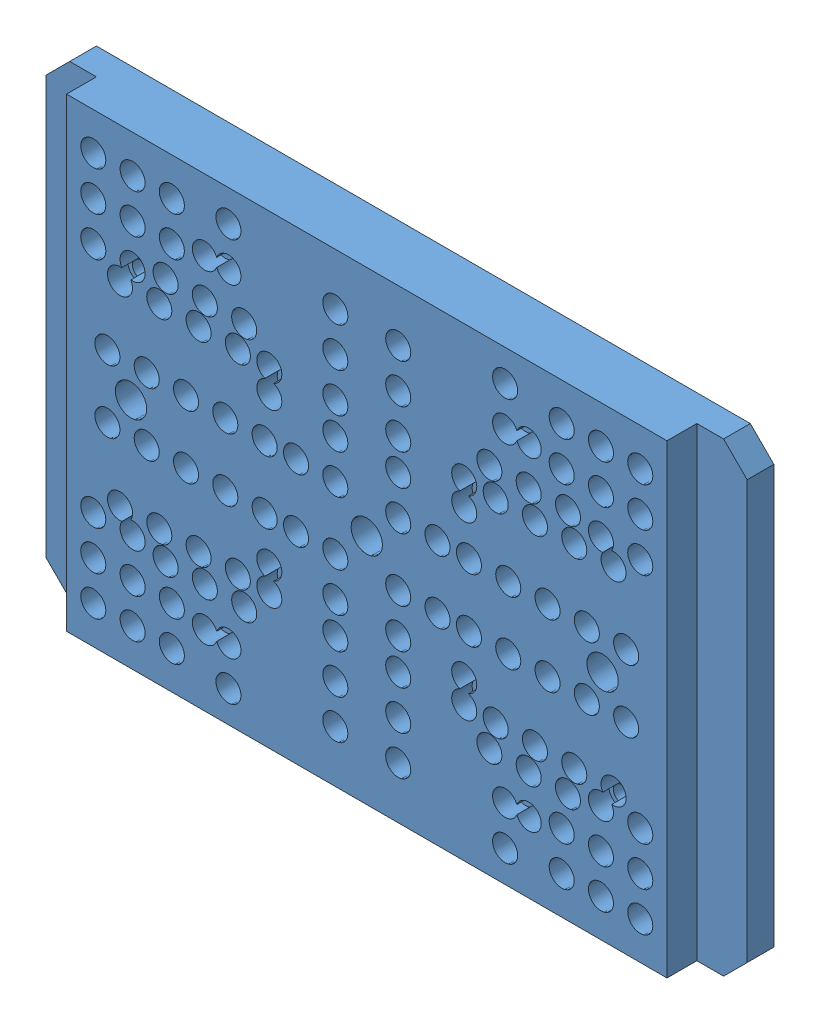
SolidWorks assembly H1000 C800 ROBO 5X v1, configuration Défaut. Lengths in mm.
Overall size (446 296 36).
2 component instances, 1 part files, 0 mates.
Components (placement in the parent):
- H1000 C800 ROBO 5X v1(2)^H1000 C800 ROBO 5X-1: H1000 C800 ROBO 5X v1(2)^H1000 C800 ROBO 5X [Défaut] at origin size (446 296 36) (virtual)
  - ^H1000 C800 ROBO 5X v1(2)_H1000 C800 ROBO 5X-1: ^H1000 C800 ROBO 5X v1(2)_H1000 C800 ROBO 5X [Défaut] at (224.5113 1620.1921 -470) size (446 296 36) (virtual)
